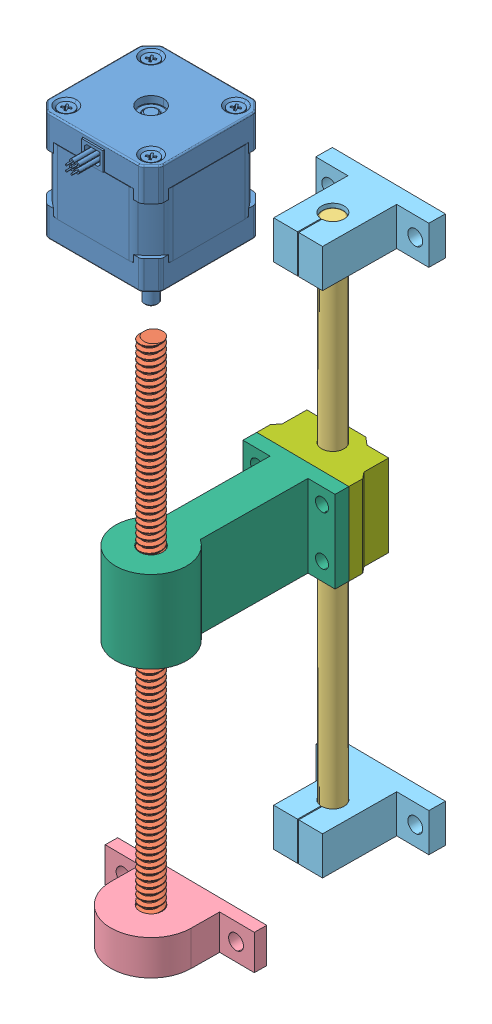
SolidWorks assembly replica-v003, configuration Default. Lengths in mm.
Overall size (55.26 273.05 116.58).
8 component instances, 7 part files, 8 mates.
Components (placement in the parent):
- Nema17-1: Nema17 [Default] at (-46.7057 69.8353 -4.5862) x (-1 0 0) z (0 0 1) size (42.3 62.01 51.35)
- threaded-rod-1: threaded-rod [Default] at (-46.7057 -3.1568 -4.5862) x (0.952048 0 -0.30595) z (0 -1 0) size (8.28 9.24 200.12)
- smooth-rod-1: smooth-rod [Default] at (-46.1306 2.1481 -70.4837) x (0.999962 0 0.008727) z (0 -1 0) size (8 8 200)
- threaded-rod-holder-1: threaded-rod-holder [Default] at (-46.5757 -183.2647 -19.4857) x (0.999962 0 0.008727) z (0 -1 0) size (55 29.61 12.8)
- smooth-rod-holder-1: smooth-rod-holder [Default] at (-45.9535 -182.6647 -90.7829) x (0.999962 0 0.008727) z (0 -1 0) size (41.7 32.9 14)
- smooth-rod-holder-2: smooth-rod-holder [Default] at (-45.9535 3.3353 -90.7829) x (0.999962 0 0.008727) z (0 -1 0) size (41.7 32.9 14)
- cartridge-v001-1: cartridge-v001 [Default] at (-46.2258 -99.4881 -59.5841) x (-0.008727 0 0.999962) z (-0.999962 0 -0.008727) size (68 30 34)
- linear-bearing-1: linear-bearing [Default] at (-46.2258 -99.4881 -59.5841) x (0.999962 0 0.008727) z (0 1 0) size (34 18.67 30)
Mates (geometry in assembly coordinates):
- Concentric3: concentric aligned: cylinder of threaded-rod-1 through (-46.7057 -203.1568 -4.5862) axis (0 1 0) radius 4; cylinder of threaded-rod-holder-1 through (-46.7057 -196.0647 -4.5862) axis (0 1 0) radius 4.1
- Concentric4: concentric aligned: cylinder of smooth-rod-1 through (-46.1306 -197.8519 -70.4837) axis (0 1 0) radius 4; cylinder of smooth-rod-holder-1 through (-46.1306 -196.6647 -70.4837) axis (0 1 0) radius 4.15
- Concentric5: concentric aligned: cylinder of smooth-rod-1 through (-46.1306 -197.8519 -70.4837) axis (0 1 0) radius 4; cylinder of smooth-rod-holder-2 through (-46.1306 -10.6647 -70.4837) axis (0 1 0) radius 4.15
- Concentric6: concentric anti-aligned: cylinder of threaded-rod-1 through (-46.7057 -203.1568 -4.5862) axis (0 1 0) radius 4; cylinder of cartridge-v001-1 through (-46.7057 -69.4881 -4.5862) axis (0 -1 0) radius 4.25
- Coincident4: coincident anti-aligned: line of cartridge-v001-1 through (-29.2264 -69.4881 -59.4358) axis (-0.999962 0 -0.008727); line of linear-bearing-1 through (-63.2251 -69.4881 -59.7325) axis (0.999962 0 0.008727)
- Coincident5: coincident aligned: line of cartridge-v001-1 through (-63.2251 -69.4881 -59.7325) axis (0 -1 0); line of linear-bearing-1 through (-63.2251 -69.4881 -59.7325) axis (0 -1 0)
- Concentric7: concentric anti-aligned: cylinder of smooth-rod-1 through (-46.1306 -197.8519 -70.4837) axis (0 1 0) radius 4; cylinder of linear-bearing-1 through (-46.1306 -69.4881 -70.4837) axis (0 -1 0) radius 4.1
- Concentric11: concentric aligned: cylinder of Nema17-1 through (-46.7057 7.8353 -4.5862) axis (0 1 0) radius 2.5; cylinder of threaded-rod-1 through (-46.7057 -203.1568 -4.5862) axis (0 1 0) radius 4
